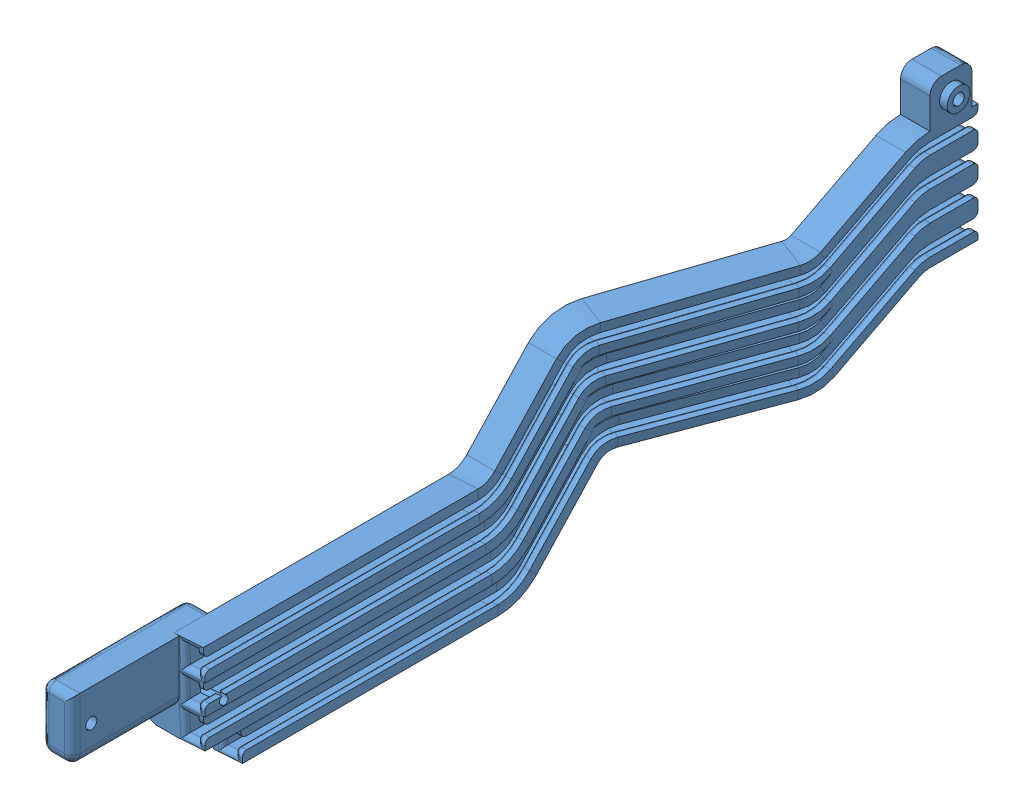
SolidWorks assembly cSL cap guide S3, configuration Default. Lengths in mm.
Overall size (32.15 83.17 214.8).
5 component instances, 2 part files, 4 mates.
Components (placement in the parent):
- cSL cap guides-1: cSL cap guides [31] at origin size (23.53 46.05 186.8) (hidden)
- cSL cap guides-2: cSL cap guides [32] at origin size (23.54 46.06 186.8) (hidden)
- cSL cap guides-3: cSL cap guides [33] at origin size (23.55 46.07 186.8) (hidden)
- cSL cap guides-4: cSL cap guides [34] at origin size (23.56 46.08 177) (hidden)
- csl cap guide s3^cSL cap guide S3-1: csl cap guide s3^cSL cap guide S3 [Default] at (-27.9 0 0) x (0 0 -1) z (1 0 0) size (214.8 83.17 32.15) (virtual)
Mates (geometry in assembly coordinates):
- InPlace1: in place: plane of ? through (-27.9 133.6 -652.4384) normal (1 0 0); plane of csl cap guide s3^cSL cap guide S3-1 through (-27.9 0 0) normal (1 0 0); moOrthogonalPlaneRef_w of ? through (-27.9 133.6 -652.4384) normal (1 0 0); line of csl cap guide s3^cSL cap guide S3-1 through (-55 -27.9 0) axis (0 0 1); plane of ? through (-27.9 133.6 -652.4384) normal (1 0 0); plane of csl cap guide s3^cSL cap guide S3-1 through (-27.9 0 0) normal (0 0 -1); plane of ? through (-27.9 133.6 -652.4384) normal (1 0 0); unknown of csl cap guide s3^cSL cap guide S3-1
- Coincident1: coincident aligned: plane of cSL cap guides-1; plane of ?
- Coincident2: coincident aligned: moOrthogonalPlaneRef_w of cSL cap guides-1 through (-27.9 0 0) normal (0 1 0); plane of csl cap guide s3^cSL cap guide S3-1
- Coincident3: coincident anti-aligned: moOrthogonalPlaneRef_w of cSL cap guides-1 through (-27.9 0 0) normal (0 0 1); plane of csl cap guide s3^cSL cap guide S3-1 through (-27.9 0 0) normal (0 0 -1)
